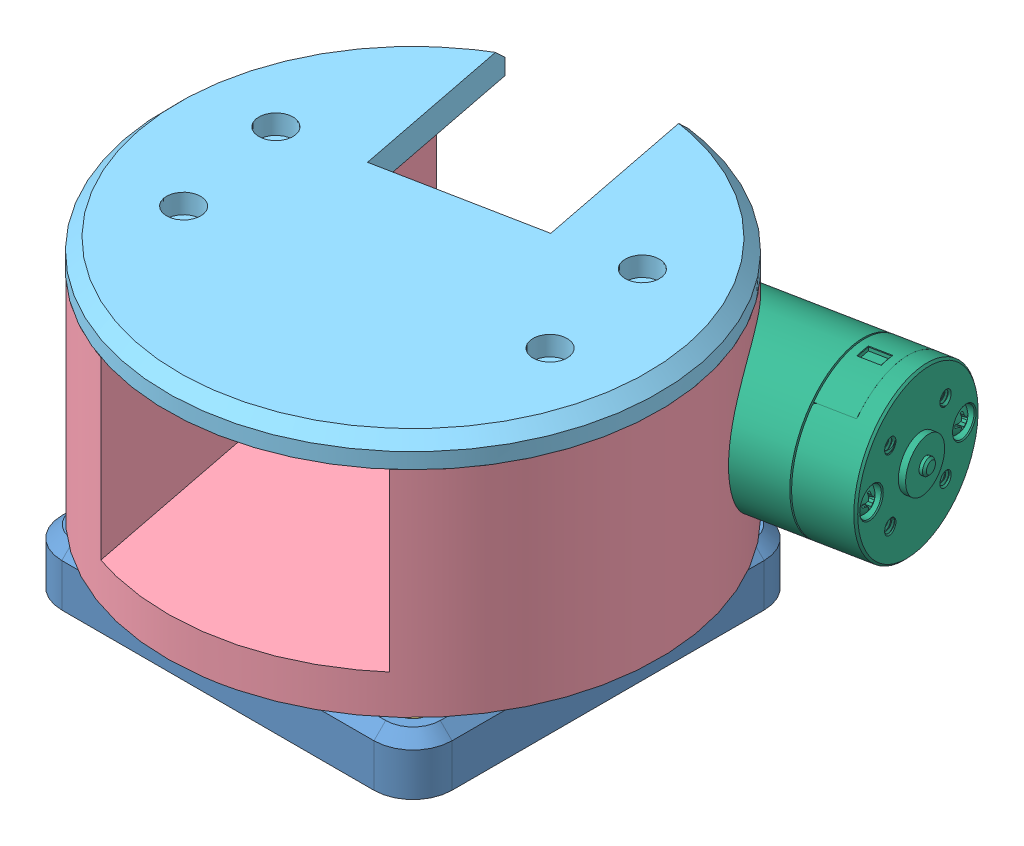
SolidWorks assembly TurretFullAssembly, configuration Default. Lengths in mm.
Overall size (163.22 80.89 147.92).
9 component instances, 6 part files, 19 mates.
Components (placement in the parent):
- TurretMountingPlate-1: TurretMountingPlate [Default] at (39.4302 47.8055 73.8689) size (100 14 100)
- 5972K365_Ball Bearing-1: 5972K365_Ball Bearing [5972K365] at (39.4302 54.8055 73.8689) x (1 0 0) z (0 1 0) size (62 62 14)
- 91292A125_18-8 Stainless Steel Socket Head Screw-1: 91292A125_18-8 Stainless Steel Socket Head Screw [91292A125] at (-0.5698 44.8055 113.8689) x (0.607359 0 0.794427) z (0 -1 0) size (8.5 8.5 17.42)
- 91292A125_18-8 Stainless Steel Socket Head Screw-2: 91292A125_18-8 Stainless Steel Socket Head Screw [91292A125] at (79.4302 44.8055 33.8689) x (0.610419 0 0.792079) z (0 -1 0) size (8.5 8.5 17.42)
- 91292A125_18-8 Stainless Steel Socket Head Screw-3: 91292A125_18-8 Stainless Steel Socket Head Screw [91292A125] at (-0.5698 44.8055 33.8689) x (0.606115 0 0.795377) z (0 -1 0) size (8.5 8.5 17.42)
- 91292A125_18-8 Stainless Steel Socket Head Screw-4: 91292A125_18-8 Stainless Steel Socket Head Screw [91292A125] at (79.4302 44.8055 113.8689) x (0.999476 0 -0.032384) z (0 -1 0) size (8.5 8.5 17.42)
- TurretBearingMount-1: TurretBearingMount [Default] at (39.4302 48.5055 73.8689) x (0.981263 0 -0.192675) z (0.192675 0 0.981263) size (126 70 126)
- TurretBearingRoof-1: TurretBearingRoof [Default] at (39.4302 118.5055 73.8689) x (0.981263 0 -0.192675) z (0.192675 0 0.981263) size (126 7 122.74)
- 6331K12_Compact Round-Face DC Motor-1: 6331K12_Compact Round-Face DC Motor [6331K12] at (87.7667 93.5055 33.805) x (0.192675 0 0.981263) z (-0.981263 0 0.192675) size (40.13 40.13 72.69)
Mates (geometry in assembly coordinates):
- Concentric1: concentric anti-aligned: cylinder of TurretMountingPlate-1 through (39.4302 61.8055 73.8689) axis (0 -1 0) radius 31; cylinder of 5972K365_Ball Bearing-1 through (39.4302 61.8055 73.8689) axis (0 1 0) radius 31
- Coincident1: coincident aligned: plane of TurretMountingPlate-1 through (-0.5698 47.8055 113.8689) normal (0 -1 0); plane of 5972K365_Ball Bearing-1 through (39.4302 47.8055 43.5689) normal (0 -1 0)
- Concentric3: concentric anti-aligned: cylinder of TurretMountingPlate-1 through (-0.5698 56.8055 113.8689) axis (0 1 0) radius 4.375; cylinder of 91292A125_18-8 Stainless Steel Socket Head Screw-1 through (-0.5698 61.8055 113.8689) axis (0 -1 0) radius 4.25
- Coincident3: coincident anti-aligned: plane of TurretMountingPlate-1 through (-0.5698 56.8055 113.8689) normal (0 1 0); plane of 91292A125_18-8 Stainless Steel Socket Head Screw-1 through (-0.5698 56.8055 113.8689) normal (0 -1 0)
- Concentric4: concentric anti-aligned: cylinder of TurretMountingPlate-1 through (-0.5698 56.8055 33.8689) axis (0 1 0) radius 4.375; cylinder of 91292A125_18-8 Stainless Steel Socket Head Screw-3 through (-0.5698 61.8055 33.8689) axis (0 -1 0) radius 4.25
- Concentric5: concentric anti-aligned: cylinder of TurretMountingPlate-1 through (79.4302 56.8055 33.8689) axis (0 1 0) radius 4.375; cylinder of 91292A125_18-8 Stainless Steel Socket Head Screw-2 through (79.4302 61.8055 33.8689) axis (0 -1 0) radius 4.25
- Concentric6: concentric anti-aligned: cylinder of TurretMountingPlate-1 through (79.4302 56.8055 113.8689) axis (0 1 0) radius 4.375; cylinder of 91292A125_18-8 Stainless Steel Socket Head Screw-4 through (79.4302 61.8055 113.8689) axis (0 -1 0) radius 4.25
- Coincident4: coincident anti-aligned: plane of TurretMountingPlate-1 through (79.4302 56.8055 33.8689) normal (0 1 0); plane of 91292A125_18-8 Stainless Steel Socket Head Screw-2 through (79.4302 56.8055 33.8689) normal (0 -1 0)
- Coincident5: coincident anti-aligned: plane of TurretMountingPlate-1 through (79.4302 56.8055 113.8689) normal (0 1 0); plane of 91292A125_18-8 Stainless Steel Socket Head Screw-4 through (79.4302 56.8055 113.8689) normal (0 -1 0)
- Coincident6: coincident anti-aligned: plane of TurretMountingPlate-1 through (-0.5698 56.8055 33.8689) normal (0 1 0); plane of 91292A125_18-8 Stainless Steel Socket Head Screw-3 through (-0.5698 56.8055 33.8689) normal (0 -1 0)
- Concentric7: concentric anti-aligned: cylinder of 5972K365_Ball Bearing-1 through (39.4302 61.8055 73.8689) axis (0 1 0) radius 17.4995; cylinder of TurretBearingMount-1 through (39.4302 63.5055 73.8689) axis (0 -1 0) radius 17.5
- Coincident8: coincident anti-aligned: circle of 5972K365_Ball Bearing-1; plane of TurretBearingMount-1 through (39.4302 48.5055 73.8689) normal (0 -1 0)
- Concentric8: concentric aligned: cylinder of TurretBearingMount-1 through (39.4302 73.5055 73.8689) axis (0 -1 0) radius 63; cylinder of TurretBearingRoof-1 through (39.4302 125.5055 73.8689) axis (0 -1 0) radius 63
- Concentric9: concentric aligned: cylinder of TurretBearingMount-1 through (81.5708 112.5055 80.8809) axis (0 1 0) radius 2.625; cylinder of TurretBearingRoof-1 through (81.5708 120.5055 80.8809) axis (0 1 0) radius 4.375
- Concentric10: concentric aligned: cylinder of TurretBearingMount-1 through (75.7905 112.5055 51.443) axis (0 1 0) radius 2.625; cylinder of TurretBearingRoof-1 through (75.7905 120.5055 51.443) axis (0 1 0) radius 4.375
- Coincident9: coincident anti-aligned: plane of TurretBearingMount-1 through (39.4302 118.5055 73.8689) normal (0 1 0); plane of TurretBearingRoof-1 through (39.4302 118.5055 73.8689) normal (0 -1 0)
- Coincident10: coincident anti-aligned: plane of TurretBearingMount-1 through (81.7614 118.5055 110.3972) normal (0.981263 0 -0.192675); plane of 6331K12_Compact Round-Face DC Motor-1 through (67.5035 99.8555 37.7837) normal (-0.981263 0 0.192675)
- Concentric11: concentric anti-aligned: cylinder of TurretBearingMount-1 through (9.0511 93.5055 49.2611) axis (0.981263 0 -0.192675) radius 20; cylinder of 6331K12_Compact Round-Face DC Motor-1 through (53.4961 93.5055 40.5341) axis (-0.981263 0 0.192675) radius 20.066
- Concentric12: concentric anti-aligned: cylinder of TurretBearingMount-1 through (44.7891 84.5252 33.0921) axis (0.981263 0 -0.192675) radius 2; circle of 6331K12_Compact Round-Face DC Motor-1
